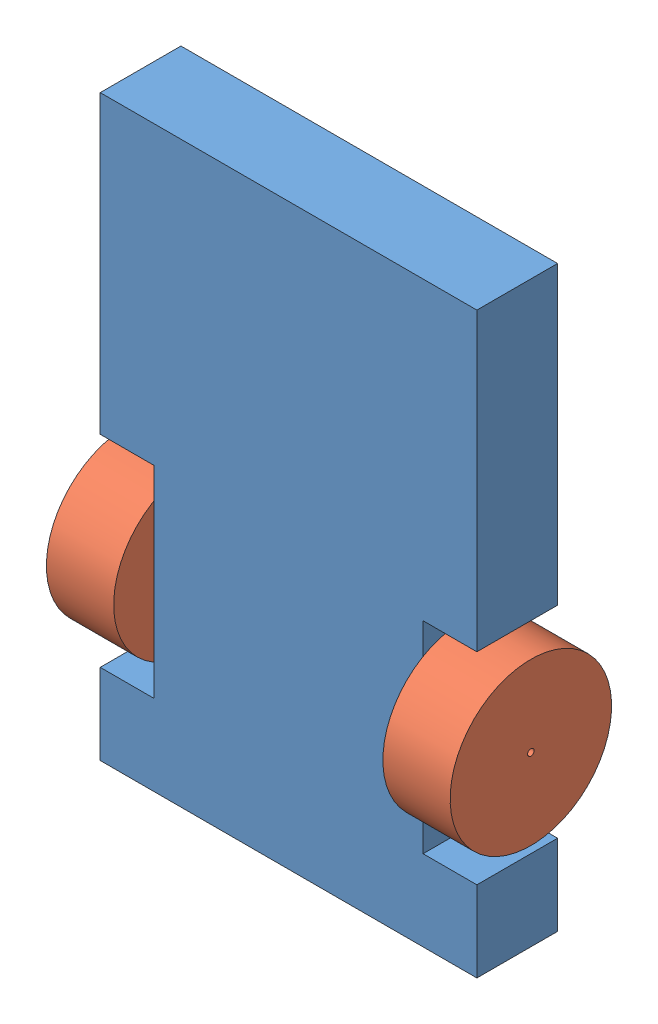
SolidWorks assembly Fertiges Modell mit Drehung, configuration Standard. Lengths in mm.
Overall size (150.06 216 101.79).
4 component instances, 3 part files, 5 mates.
Components (placement in the parent):
- Alphabot Grundgerüst-1: Alphabot Grundgerüst [Standard] at (-79.3411 -93.8192 3.5) size (140 215 67)
- Reifen-1: Reifen [Standard] at (40.7195 -26.1905 18.5) x (0 -0.525709 -0.850665) z (1 0 0) size (60 60 25)
- Reifen-2: Reifen [Standard] at (-84.3411 -26.1905 18.5) x (0 0.520672 -0.853757) z (1 0 0) size (60 60 25)
- Sensor-1: Sensor [Standard] at (0.6589 -85.3192 -23.5) x (-1 0 0) z (0 -1 0) size (27.5 15 22)
Mates (geometry in assembly coordinates):
- Konzentrisch1: concentric aligned: circle of Alphabot Grundgerüst-1; circle of Reifen-1
- Deckungsgleich2: coincident anti-aligned: plane of Alphabot Grundgerüst-1 through (-59.3411 -63.8192 33.5) normal (-1 0 0); plane of Reifen-2 through (-59.3411 -26.1905 18.5) normal (1 0 0)
- Konzentrisch7: concentric aligned: circle of Alphabot Grundgerüst-1; circle of Reifen-2
- Konzentrisch8: concentric aligned: circle of Alphabot Grundgerüst-1; circle of Reifen-1
- Deckungsgleich5: coincident: point of Alphabot Grundgerüst-1; point of Sensor-1
